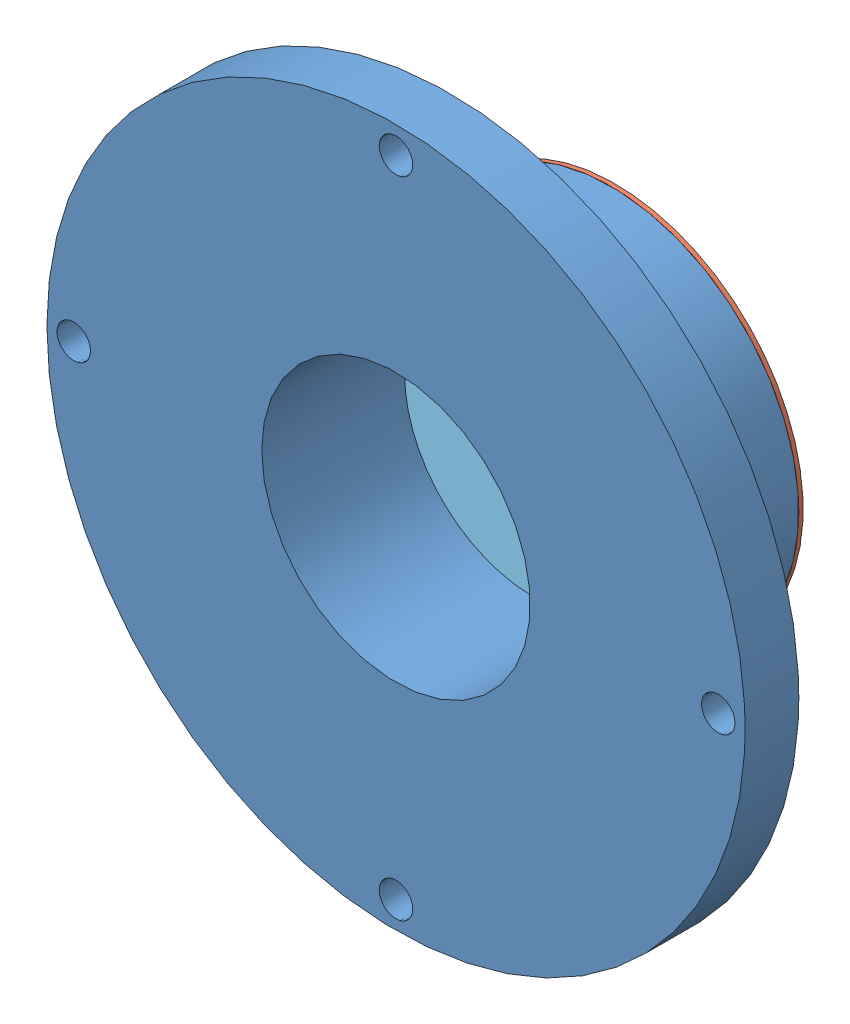
SolidWorks assembly ESI_Ring_Assembly, configuration Default. Lengths in mm.
Overall size (82.55 82.55 25.91).
8 component instances, 5 part files, 15 mates.
Components (placement in the parent):
- ESI_Ring_Housing-1: ESI_Ring_Housing [Default] at origin size (82.55 82.55 25.4)
- ESI_Terminal_Ring-1: ESI_Terminal_Ring [Default] at (0 0 -0.508) size (44.45 44.45 0.51)
- ESI_Insulating_Ring-1: ESI_Insulating_Ring [Default] at origin size (30.48 30.48 2.54)
- ESI_Ring_LargeID-1: ESI_Ring_LargeID [Default] at (0 0 2.54) size (30.48 30.48 0.51)
- ESI_Ring_SmallID-1: ESI_Ring_SmallID [Default] at (0 0 5.588) size (30.48 30.48 0.51)
- ESI_Insulating_Ring-2: ESI_Insulating_Ring [Default] at (0 0 3.048) size (30.48 30.48 2.54)
- ESI_Ring_SmallID-2: ESI_Ring_SmallID [Default] at (0 0 8.636) size (30.48 30.48 0.51)
- ESI_Insulating_Ring-3: ESI_Insulating_Ring [Default] at (0 0 6.096) size (30.48 30.48 2.54)
Mates (geometry in assembly coordinates):
- Coincident1: coincident anti-aligned: axis of ESI_Ring_Housing-1 through (0 18.415 7.5946) axis (0 0 -1); axis of ESI_Terminal_Ring-1 through (0 18.415 -0.508) axis (0 0 1)
- Coincident2: coincident anti-aligned: axis of ESI_Ring_Housing-1 through (0 -18.415 7.5946) axis (0 0 -1); axis of ESI_Terminal_Ring-1 through (0 -18.415 -0.508) axis (0 0 1)
- Coincident3: coincident anti-aligned: plane of ESI_Ring_Housing-1 through (0 0 0) normal (0 0 -1); plane of ESI_Terminal_Ring-1 through (0 0 0) normal (0 0 1)
- Coincident4: coincident aligned: axis of ESI_Ring_Housing-1 through (0 0 25.4) axis (0 0 -1); axis of ESI_Insulating_Ring-1 through (0 0 2.54) axis (0 0 -1)
- Coincident5: coincident aligned: axis of ESI_Insulating_Ring-1 through (0 0 2.54) axis (0 0 -1); axis of ESI_Ring_LargeID-1 through (0 0 3.048) axis (0 0 -1)
- Coincident6: coincident aligned: plane of ESI_Insulating_Ring-1 through (0 0 2.54) normal (0 0 1); circle of ESI_Ring_LargeID-1
- Coincident7: coincident aligned: plane of ESI_Terminal_Ring-1 through (0 0 0) normal (0 0 1); circle of ESI_Insulating_Ring-1
- Coincident8: coincident aligned: axis of ESI_Insulating_Ring-2 through (0 0 5.588) axis (0 0 -1); axis of ESI_Ring_SmallID-1 through (0 0 6.096) axis (0 0 -1)
- Coincident9: coincident aligned: axis of ESI_Ring_Housing-1 through (0 0 25.4) axis (0 0 -1); axis of ESI_Ring_SmallID-1 through (0 0 6.096) axis (0 0 -1)
- Coincident10: coincident aligned: circle of ESI_Ring_SmallID-1; plane of ESI_Insulating_Ring-2 through (0 0 5.588) normal (0 0 1)
- Coincident11: coincident aligned: plane of ESI_Ring_LargeID-1 through (0 0 3.048) normal (0 0 1); circle of ESI_Insulating_Ring-2
- Coincident12: coincident aligned: axis of ESI_Ring_SmallID-2 through (0 0 9.144) axis (0 0 -1); axis of ESI_Insulating_Ring-3 through (0 0 8.636) axis (0 0 -1)
- Coincident13: coincident aligned: circle of ESI_Ring_SmallID-2; plane of ESI_Insulating_Ring-3 through (0 0 8.636) normal (0 0 1)
- Coincident14: coincident aligned: axis of ESI_Ring_Housing-1 through (0 0 25.4) axis (0 0 -1); axis of ESI_Ring_SmallID-2 through (0 0 9.144) axis (0 0 -1)
- Coincident15: coincident aligned: plane of ESI_Ring_SmallID-1 through (0 0 6.096) normal (0 0 1); circle of ESI_Insulating_Ring-3
